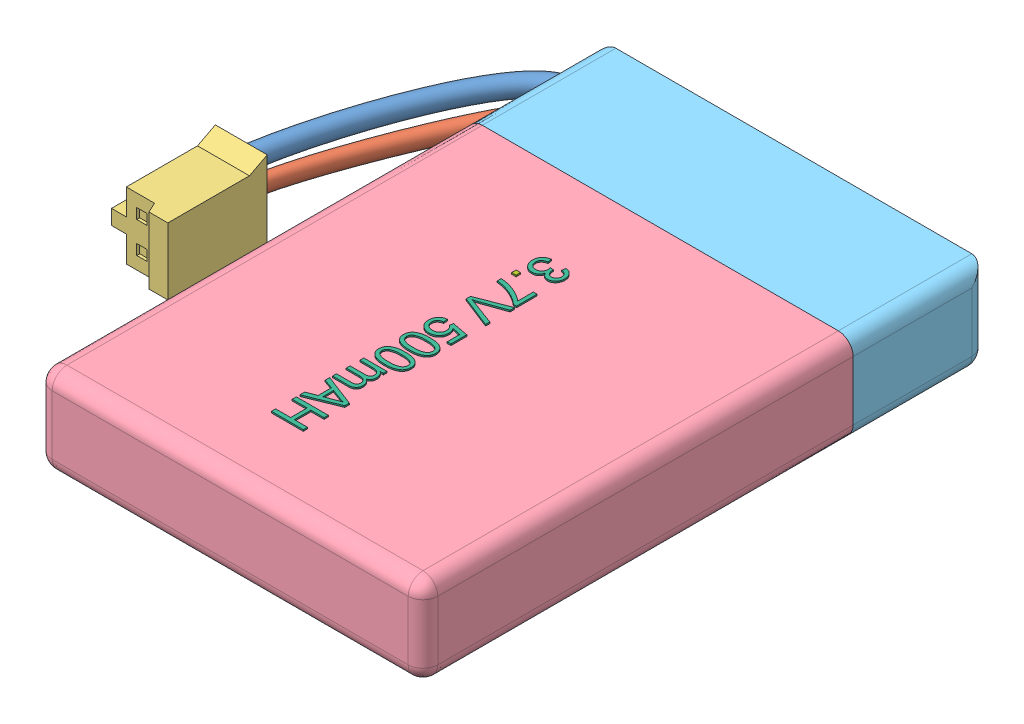
SolidWorks assembly 3.3V 500Mah Battery v2, configuration Predeterminado. Lengths in mm.
Overall size (34.6 6.63 38.21).
7 component instances, 7 part files, 0 mates.
Components (placement in the parent):
- Black wIRE-1: Black wIRE [Predeterminado] at (-17 0.9 -20) size (7.14 2.41 17.5)
- Red Wire-1: Red Wire [Predeterminado] at (-17 0.9 -20) size (7.13 1.93 17.65)
- Connector-1: Connector [Predeterminado] at (-17 0.9 -20) size (4.5 5.75 6.7)
- Body1-1: Body1 [Predeterminado] at origin size (26.21 6.21 29.1)
- Body2-1: Body2 [Predeterminado] at origin size (26.21 6.1 9.1)
- Text-1: Text [Predeterminado] at origin size (2.27 0.1 18.35)
- Text (1)-1: Text (1) [Predeterminado] at origin size (0.3 0.1 0.3)
